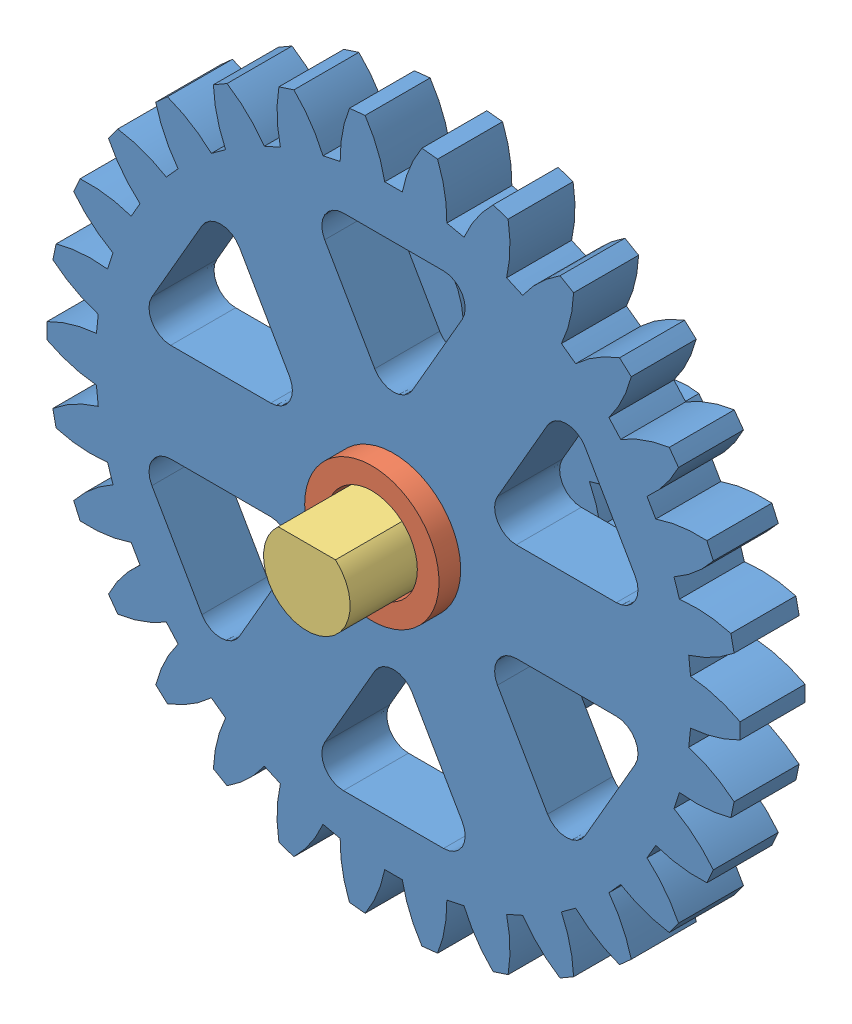
SolidWorks assembly input#2(30T-1.0Mod 15mm shaft), configuration Default. Lengths in mm.
Overall size (32 31.89 15).
6 component instances, 3 part files, 10 mates.
Components (placement in the parent):
- root_gear.-1: root_gear. [30T1.0Mod] at (5.9976 7.6843 12.878) size (32 31.89 3)
- root_gear.-2: root_gear. [10T 1.5Mod] at (5.9976 7.6843 8.878) size (18 17.3 3)
- spacer-1: spacer [4.2 1mm] at (5.9976 7.6843 15.878) size (6.2 6.2 1)
- spacer-2: spacer [4.2 1mm] at (5.9976 7.6843 11.878) x (0.997387 0.07225 0) z (0 0 1) size (6.2 6.2 1)
- spacer-5: spacer [4.2 1mm] at (5.9976 7.6843 7.878) x (0.9453 0.326202 0) z (0 0 1) size (6.2 6.2 1)
- axle-2: axle [axle15] at (5.9976 7.6843 4.878) size (4 3.5 15)
Mates (geometry in assembly coordinates):
- Coincident4: coincident anti-aligned: plane of root_gear.-2 through (5.9976 7.6843 8.878) normal (0 0 -1); plane of spacer-5 through (5.9976 7.6843 8.878) normal (0 0 1)
- Coincident5: coincident anti-aligned: plane of root_gear.-1 through (5.9976 7.6843 12.878) normal (0 0 -1); plane of spacer-2 through (5.9976 7.6843 12.878) normal (0 0 1)
- Coincident6: coincident anti-aligned: plane of root_gear.-2 through (5.9976 7.6843 11.878) normal (0 0 1); plane of spacer-2 through (5.9976 7.6843 11.878) normal (0 0 -1)
- Coincident7: coincident aligned: plane of root_gear.-1 through (5.9976 7.6843 15.878) normal (0 0 1); circle of spacer-1
- Concentric2: concentric aligned: cylinder of root_gear.-2 through (5.9976 7.6843 18.878) axis (0 0 -1) radius 2; cylinder of axle-2 through (5.9976 7.6843 19.878) axis (0 0 -1) radius 2
- Concentric3: concentric aligned: cylinder of spacer-5 through (5.9976 7.6843 8.878) axis (0 0 -1) radius 2.1; cylinder of axle-2 through (5.9976 7.6843 19.878) axis (0 0 -1) radius 2
- Concentric4: concentric aligned: cylinder of spacer-2 through (5.9976 7.6843 12.878) axis (0 0 -1) radius 2.1; cylinder of axle-2 through (5.9976 7.6843 19.878) axis (0 0 -1) radius 2
- Concentric5: concentric aligned: cylinder of root_gear.-1 through (5.9976 7.6843 22.878) axis (0 0 -1) radius 2; cylinder of axle-2 through (5.9976 7.6843 19.878) axis (0 0 -1) radius 2
- Concentric6: concentric aligned: cylinder of spacer-1 through (5.9976 7.6843 16.878) axis (0 0 -1) radius 2.1; cylinder of axle-2 through (5.9976 7.6843 19.878) axis (0 0 -1) radius 2
- Distance1: distance = 3 mm aligned: plane of spacer-1 through (5.9976 7.6843 16.878) normal (0 0 1); plane of axle-2 through (5.9976 7.6843 19.878) normal (0 0 1)
